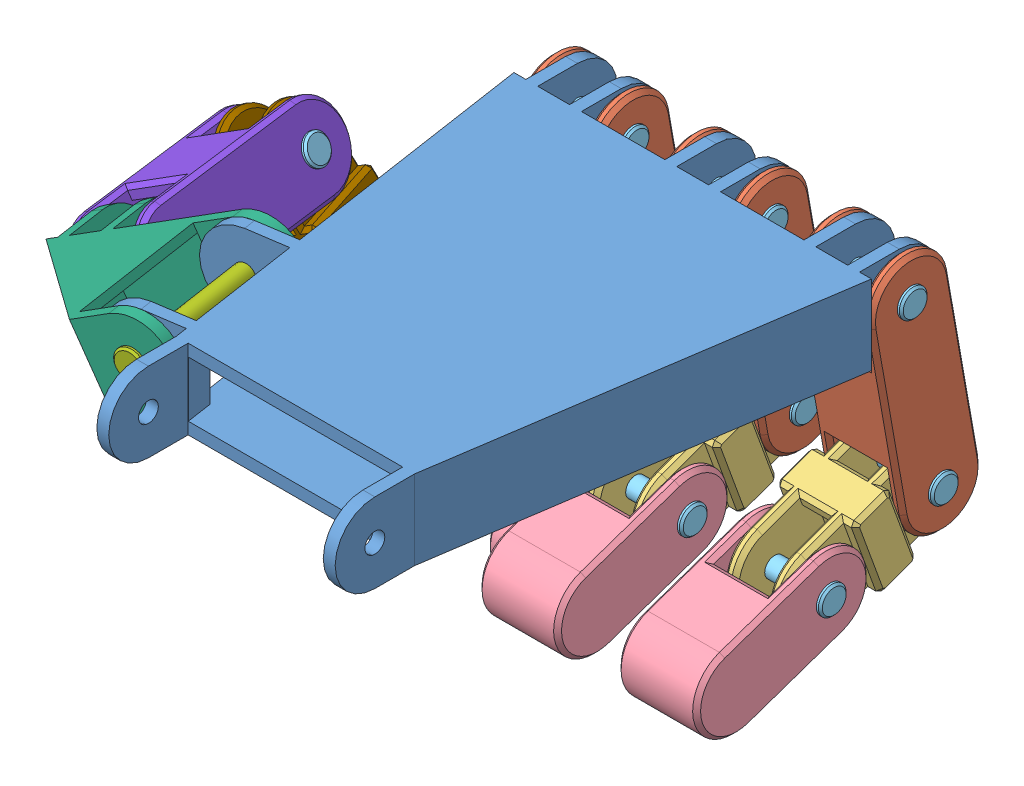
SolidWorks assembly Robot_Hand_Right, configuration Default. Lengths in mm.
Overall size (150.89 119.07 160.36).
29 component instances, 9 part files, 21 mates.
Components (placement in the parent):
- hand_palm_right-1: hand_palm_right [Default] at origin size (100.27 20 140)
- Robot_Finger-1: Robot_Finger [Default] at (35 0 -10) x (0 0.984808 0.173648) z (-1 0 0) size (75.56 77.26 22) (flexible)
  - finger_inner-1: finger_inner [Default] at (-22.5 0 0) x (-1 0 0) z (0 0 -1) size (65 20 20)
  - finger_middle-1: finger_middle [Default] at (-47.6047 -14.7721 0) x (-0.173648 -0.984808 0) z (0 0 -1) size (50 20 20)
  - finger_top-1: finger_top [Default] at (-52.1649 -41.8903 0) x (-0.156434 -0.987688 0) z (0 0 -1) size (45 20 20)
  - finger_connector-1: finger_connector [Default] x (1 0 0) z (0 0 -1) size (7 7 22)
  - finger_connector-2: finger_connector [Default] at (-45 0 0) x (0.984808 -0.173648 0) z (0 0 -1) size (7 7 22)
  - finger_connector-3: finger_connector [Default] at (-50.2094 -29.5442 0) x (-0.156434 -0.987688 0) z (0 0 -1) size (7 7 22)
- Robot_Finger-2: Robot_Finger [Default] at (0 0 -10) x (0 0.984808 0.173648) z (-1 0 0) size (75.56 77.26 22) (flexible)
  - finger_inner-1: finger_inner [Default] at (-22.5 0 0) x (-1 0 0) z (0 0 -1) size (65 20 20)
  - finger_middle-1: finger_middle [Default] at (-47.6047 -14.7721 0) x (-0.173648 -0.984808 0) z (0 0 -1) size (50 20 20)
  - finger_top-1: finger_top [Default] at (-52.1649 -41.8903 0) x (-0.156434 -0.987688 0) z (0 0 -1) size (45 20 20)
  - finger_connector-1: finger_connector [Default] x (1 0 0) z (0 0 -1) size (7 7 22)
  - finger_connector-2: finger_connector [Default] at (-45 0 0) x (0.984808 -0.173648 0) z (0 0 -1) size (7 7 22)
  - finger_connector-3: finger_connector [Default] at (-50.2094 -29.5442 0) x (-0.156434 -0.987688 0) z (0 0 -1) size (7 7 22)
- Robot_Finger-3: Robot_Finger [Default] at (-35 0 -10) x (0 0.984808 0.173648) z (-1 0 0) size (110.71 49.05 22) (flexible)
  - finger_inner-1: finger_inner [Default] at (-22.5 0 0) x (-1 0 0) z (0 0 -1) size (65 20 20)
  - finger_middle-1: finger_middle [Default] at (-59.9977 -0.2618 0) x (-0.999848 -0.017452 0) z (0 0 -1) size (50 20 20)
  - finger_top-1: finger_top [Default] at (-81.0556 -11.4563 0) x (-0.48481 -0.87462 0) z (0 0 -1) size (45 20 20)
  - finger_connector-1: finger_connector [Default] x (1 0 0) z (0 0 -1) size (7 7 22)
  - finger_connector-2: finger_connector [Default] at (-45 0 0) x (0.017452 -0.999848 0) z (0 0 -1) size (7 7 22)
  - finger_connector-3: finger_connector [Default] at (-74.9954 -0.5236 0) x (-0.48481 -0.87462 0) z (0 0 -1) size (7 7 22)
- thumb_plate-1: thumb_plate [Default] at (-48.4812 -4.9517 102.7722) x (-0.859181 -0.495175 0.128877) z (0.14834 0 0.988936) size (60 20 60)
- thumb_plate_connector-1: thumb_plate_connector [Default] at (-42.8562 0 81.7047) x (-0.859181 -0.495175 0.128877) z (0.14834 0 0.988936) size (7 7 42)
- Robot_Thumb-1: Robot_Thumb [Default] at (-81.6736 -19.807 57.1917) x (-0.139771 -0.015163 -0.990068) z (0.859181 0.495175 -0.128877) size (67.66 57.64 22) (flexible)
  - thumb_inner-1: thumb_inner [Default] at (20 0 0) size (60 20 20)
  - thumb_top-1: thumb_top [Default] at (43.0388 -17.2341 0) x (0.173648 -0.984808 0) z (0 0 1) size (55 20 20)
  - finger_connector-1: finger_connector [Default] at origin size (7 7 22)
  - finger_connector-2: finger_connector [Default] at (40 0 0) x (0.173648 -0.984808 0) z (0 0 1) size (7 7 22)
Mates (geometry in assembly coordinates):
- Coincident1: coincident aligned: plane of hand_palm_right-1 through (0 0 0) normal (0 0 1); plane of assembly through (0 0 0) normal (0 0 1)
- Coincident2: coincident aligned: plane of hand_palm_right-1 through (0 0 0) normal (0 1 0); plane of assembly through (0 0 0) normal (0 1 0)
- Coincident3: coincident aligned: plane of hand_palm_right-1 through (0 0 0) normal (1 0 0); plane of assembly through (0 0 0) normal (1 0 0)
- Concentric1: concentric aligned: cylinder of hand_palm_right-1 through (42 0 -10) axis (-1 0 0) radius 2.5; cylinder of Robot_Finger-1/finger_connector-1 through (45 0 -10) axis (-1 0 0) radius 2.5
- Coincident5: coincident anti-aligned: plane of hand_palm_right-1 through (42 0 -10) normal (1 0 0); plane of Robot_Finger-1/finger_inner-1 through (42 0 -10) normal (-1 0 0)
- LimitAngle1: limit planar angle = 1.396263 rad aligned: plane of Robot_Finger-1; plane of assembly through (0 0 0) normal (0 0 1)
- Coincident7: coincident anti-aligned: circle of hand_palm_right-1; cylinder of Robot_Finger-2/finger_connector-1 through (10 0 -10) axis (-1 0 0) radius 2.5
- Coincident8: coincident anti-aligned: plane of hand_palm_right-1 through (-7 0 -10) normal (-1 0 0); plane of Robot_Finger-2/finger_inner-1 through (-7 0 -10) normal (1 0 0)
- LimitAngle2: limit planar angle = 1.396263 rad aligned: plane of Robot_Finger-2; plane of assembly through (0 0 0) normal (0 0 1)
- Concentric2: concentric aligned: cylinder of hand_palm_right-1 through (-28 0 -10) axis (-1 0 0) radius 2.5; cylinder of Robot_Finger-3/finger_connector-1 through (-25 0 -10) axis (-1 0 0) radius 2.5
- Coincident10: coincident anti-aligned: plane of hand_palm_right-1 through (-28 0 -10) normal (1 0 0); plane of Robot_Finger-3/finger_inner-1 through (-28 0 -10) normal (-1 0 0)
- LimitAngle3: limit planar angle = 1.396263 rad aligned: plane of Robot_Finger-3; plane of assembly through (0 0 0) normal (0 0 1)
- Concentric3: concentric anti-aligned: cylinder of hand_palm_right-1 through (-45.378 0 64.8928) axis (0.14834 0 0.988936) radius 2.5; cylinder of thumb_plate_connector-1 through (-39.8894 0 101.4834) axis (-0.14834 0 -0.988936) radius 2.5
- Concentric4: concentric anti-aligned: cylinder of thumb_plate-1 through (-40.3344 0 98.5166) axis (0.14834 0 0.988936) radius 2.5; cylinder of thumb_plate_connector-1 through (-39.8894 0 101.4834) axis (-0.14834 0 -0.988936) radius 2.5
- Coincident11: coincident anti-aligned: plane of thumb_plate-1 through (-39.8894 0 101.4834) normal (0.14834 0 0.988936); plane of thumb_plate_connector-1 through (-39.8894 0 101.4834) normal (-0.14834 0 -0.988936)
- Coincident12: coincident anti-aligned: plane of hand_palm_right-1 through (-40.3344 0 98.5166) normal (0.14834 0 0.988936); plane of thumb_plate-1 through (-40.3344 0 98.5166) normal (-0.14834 0 -0.988936)
- Coincident14: coincident aligned: plane of thumb_plate-1; plane of thumb_plate_connector-1
- LimitAngle6: limit planar angle = 0.518036 rad aligned: plane of thumb_plate_connector-1; plane of hand_palm_right-1 through (-30 10 100) normal (-0.988936 0 0.14834)
- Concentric5: concentric anti-aligned: cylinder of thumb_plate-1 through (-90.2655 -24.7587 58.4804) axis (0.859181 0.495175 -0.128877) radius 2.5; cylinder of Robot_Thumb-1/finger_connector-1 through (-73.0818 -14.8552 55.9029) axis (-0.859181 -0.495175 0.128877) radius 2.5
- Coincident18: coincident anti-aligned: plane of thumb_plate-1 through (-75.6594 -16.3408 56.2895) normal (0.859181 0.495175 -0.128877); plane of Robot_Thumb-1/thumb_inner-1 through (-75.6594 -16.3408 56.2895) normal (-0.859181 -0.495175 0.128877)
- LimitAngle7: limit planar angle = 0.017453 rad anti-aligned: plane of Robot_Thumb-1/finger_connector-1; plane of thumb_plate-1 through (-48.4812 -4.9517 102.7722) normal (0.14834 0 0.988936)
